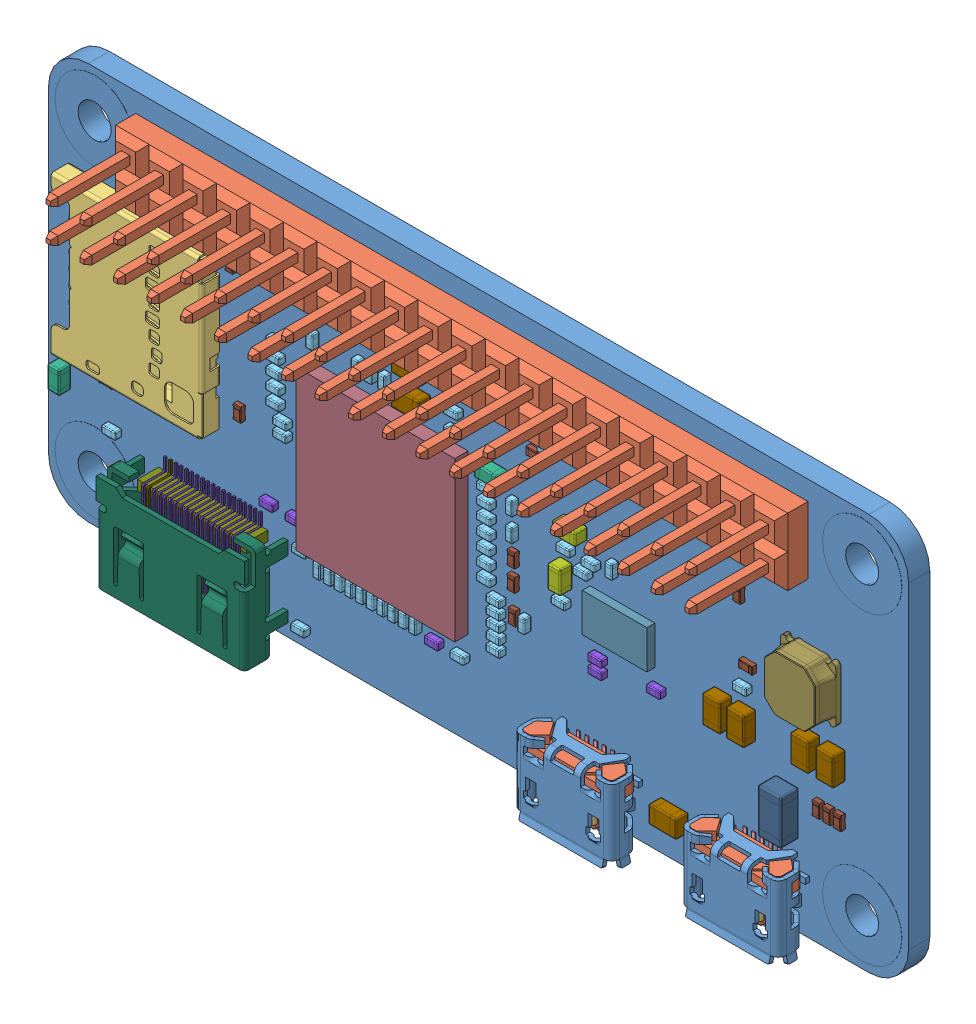
SolidWorks assembly Raspberry PI Zero W, configuration Default. Lengths in mm.
Overall size (65 30.65 11.38).
130 component instances, 22 part files, 0 mates.
Components (placement in the parent):
- Raspberry PI Zero W.step-1: Raspberry PI Zero W.step [Default] at origin size (65 32.42 20.3)
  - micro_usb_connector v17.step-1: micro_usb_connector v17.step [Default] at (41.4 3 1.74) x (0 -1 0) z (0 0 1) size (5.84 7.77 3.4)
    - shield.step-1: shield.step [Default] at origin size (5.84 7.77 3.4)
    - socket_housing.step-1: socket_housing.step [Default] at origin size (4.25 6.85 2.15)
    - socket_plate.step-1: socket_plate.step [Default] at origin size (3.38 6.8 0.31)
    - terminal.step-1: terminal.step [Default] at origin size (3.22 0.35 1.72)
    - terminal.step-2: terminal.step [Default] at (0 -1.3 0) size (3.22 0.35 1.72)
    - terminal.step-3: terminal.step [Default] at (0 -0.65 0) size (3.22 0.35 1.72)
    - terminal.step-4: terminal.step [Default] at (0 0.65 0) size (3.22 0.35 1.72)
    - terminal.step-5: terminal.step [Default] at (0 1.3 0) size (3.22 0.35 1.72)
  - micro_usb_connector v17.step-2: micro_usb_connector v17.step [Default] at (54 3 1.74) x (0 -1 0) z (0 0 1) size (5.84 7.77 3.4)
    - shield.step-1: shield.step [Default] at origin size (5.84 7.77 3.4)
    - socket_housing.step-1: socket_housing.step [Default] at origin size (4.25 6.85 2.15)
    - socket_plate.step-1: socket_plate.step [Default] at origin size (3.38 6.8 0.31)
    - terminal.step-1: terminal.step [Default] at origin size (3.22 0.35 1.72)
    - terminal.step-2: terminal.step [Default] at (0 -1.3 0) size (3.22 0.35 1.72)
    - terminal.step-3: terminal.step [Default] at (0 -0.65 0) size (3.22 0.35 1.72)
    - terminal.step-4: terminal.step [Default] at (0 0.65 0) size (3.22 0.35 1.72)
    - terminal.step-5: terminal.step [Default] at (0 1.3 0) size (3.22 0.35 1.72)
  - Components.step-1: Components.step [Default] at origin size (59.43 22.49 1.8)
    - CAPC-0402-T0.55-BN.step-1: CAPC-0402-T0.55-BN.step [Default] at (33.3698 17.6201 1.6) size (1.05 0.55 0.55)
    - CAPC-0402-T0.55-BN.step-2: CAPC-0402-T0.55-BN.step [Default] at (33.3698 16.6201 1.6) size (1.05 0.55 0.55)
    - CAPC-0402-T0.55-BN.step-3: CAPC-0402-T0.55-BN.step [Default] at (33.3698 15.6201 1.6) size (1.05 0.55 0.55)
    - CAPC-0402-T0.55-BN.step-4: CAPC-0402-T0.55-BN.step [Default] at (33.3698 14.6201 1.6) size (1.05 0.55 0.55)
    - CAPC-0402-T0.55-BN.step-5: CAPC-0402-T0.55-BN.step [Default] at (33.3698 13.6201 1.6) size (1.05 0.55 0.55)
    - CAPC-0402-T0.55-BN.step-6: CAPC-0402-T0.55-BN.step [Default] at (33.3698 12.6201 1.6) size (1.05 0.55 0.55)
    - CAPC-0402-T0.55-BN.step-7: CAPC-0402-T0.55-BN.step [Default] at (33.3698 11.6201 1.6) size (1.05 0.55 0.55)
    - CAPC-0402-T0.55-BN.step-8: CAPC-0402-T0.55-BN.step [Default] at (35.2975 17.3433 1.6) x (0 -1 0) z (0 0 1) size (1.05 0.55 0.55)
    - CAPC-0402-T0.55-BN.step-9: CAPC-0402-T0.55-BN.step [Default] at (35.2975 15.5933 1.6) x (0 -1 0) z (0 0 1) size (1.05 0.55 0.55)
    - CAPC-0402-T0.55-BN.step-10: CAPC-0402-T0.55-BN.step [Default] at (20.7555 5.9273 1.6) x (0 -1 0) z (0 0 1) size (1.05 0.55 0.55)
    - CAPC-0402-T0.55-BN.step-11: CAPC-0402-T0.55-BN.step [Default] at (21.5605 5.9273 1.6) x (0 -1 0) z (0 0 1) size (1.05 0.55 0.55)
    - CAPC-0402-T0.55-BN.step-12: CAPC-0402-T0.55-BN.step [Default] at (22.3655 5.9273 1.6) x (0 -1 0) z (0 0 1) size (1.05 0.55 0.55)
    - CAPC-0402-T0.55-BN.step-13: CAPC-0402-T0.55-BN.step [Default] at (23.1705 5.9273 1.6) x (0 -1 0) z (0 0 1) size (1.05 0.55 0.55)
    - CAPC-0402-T0.55-BN.step-14: CAPC-0402-T0.55-BN.step [Default] at (23.9755 5.9273 1.6) x (0 -1 0) z (0 0 1) size (1.05 0.55 0.55)
    - CAPC-0402-T0.55-BN.step-15: CAPC-0402-T0.55-BN.step [Default] at (24.7805 5.9273 1.6) x (0 -1 0) z (0 0 1) size (1.05 0.55 0.55)
    - CAPC-0402-T0.55-BN.step-16: CAPC-0402-T0.55-BN.step [Default] at (25.5855 5.9273 1.6) x (0 -1 0) z (0 0 1) size (1.05 0.55 0.55)
    - CAPC-0402-T0.55-BN.step-17: CAPC-0402-T0.55-BN.step [Default] at (26.3905 5.9273 1.6) x (0 -1 0) z (0 0 1) size (1.05 0.55 0.55)
    - CAPC-0402-T0.55-BN.step-18: CAPC-0402-T0.55-BN.step [Default] at (27.1955 5.9273 1.6) x (0 -1 0) z (0 0 1) size (1.05 0.55 0.55)
    - CAPC-0402-T0.55-BN.step-19: CAPC-0402-T0.55-BN.step [Default] at (28.0005 5.9273 1.6) x (0 -1 0) z (0 0 1) size (1.05 0.55 0.55)
    - CAPC-0402-T0.55-BN.step-20: CAPC-0402-T0.55-BN.step [Default] at (34.1 10.6 1.6) size (1.05 0.55 0.55)
    - CAPC-0402-T0.55-BN.step-21: CAPC-0402-T0.55-BN.step [Default] at (34.1 9.79 1.6) size (1.05 0.55 0.55)
    - CAPC-0402-T0.55-BN.step-22: CAPC-0402-T0.55-BN.step [Default] at (34.1 8.98 1.6) size (1.05 0.55 0.55)
    - CAPC-0402-T0.55-BN.step-23: CAPC-0402-T0.55-BN.step [Default] at (34.1 8.17 1.6) size (1.05 0.55 0.55)
    - CAPC-0402-T0.55-BN.step-24: CAPC-0402-T0.55-BN.step [Default] at (34.1 7.36 1.6) size (1.05 0.55 0.55)
    - CAPC-0402-T0.55-BN.step-25: CAPC-0402-T0.55-BN.step [Default] at (17.4437 19.1633 1.6) size (1.05 0.55 0.55)
    - CAPC-0402-T0.55-BN.step-26: CAPC-0402-T0.55-BN.step [Default] at (17.4437 18.1633 1.6) size (1.05 0.55 0.55)
    - CAPC-0402-T0.55-BN.step-27: CAPC-0402-T0.55-BN.step [Default] at (17.4437 17.1633 1.6) size (1.05 0.55 0.55)
    - CAPC-0402-T0.55-BN.step-28: CAPC-0402-T0.55-BN.step [Default] at (17.4437 16.1633 1.6) size (1.05 0.55 0.55)
    - CAPC-0402-T0.55-BN.step-29: CAPC-0402-T0.55-BN.step [Default] at (17.4437 15.1633 1.6) size (1.05 0.55 0.55)
    - CAPC-0402-T0.55-BN.step-30: CAPC-0402-T0.55-BN.step [Default] at (17.9697 14.164 1.6) size (1.05 0.55 0.55)
    - CAPC-0402-T0.55-BN.step-31: CAPC-0402-T0.55-BN.step [Default] at (17.9697 13.344 1.6) size (1.05 0.55 0.55)
    - CAPC-0402-T0.55-BN.step-32: CAPC-0402-T0.55-BN.step [Default] at (31.3668 5.5372 1.6) size (1.05 0.55 0.55)
    - CAPC-0402-T0.55-BN.step-33: CAPC-0402-T0.55-BN.step [Default] at (36.2259 10.107 1.6) x (0 -1 0) z (0 0 1) size (1.05 0.55 0.55)
    - CAPC-0402-T0.55-BN.step-34: CAPC-0402-T0.55-BN.step [Default] at (30.8759 20.015 1.6) size (1.05 0.55 0.55)
    - CAPC-0402-T0.55-BN.step-35: CAPC-0402-T0.55-BN.step [Default] at (25.6574 20.7007 1.6) x (0 -1 0) z (0 0 1) size (1.05 0.55 0.55)
    - CAPC-0402-T0.55-BN.step-36: CAPC-0402-T0.55-BN.step [Default] at (24.6574 20.7007 1.6) x (0 -1 0) z (0 0 1) size (1.05 0.55 0.55)
    - CAPC-0402-T0.55-BN.step-37: CAPC-0402-T0.55-BN.step [Default] at (23.6574 20.7007 1.6) x (0 -1 0) z (0 0 1) size (1.05 0.55 0.55)
    - CAPC-0402-T0.55-BN.step-38: CAPC-0402-T0.55-BN.step [Default] at (20.2103 20.6923 1.6) x (0 -1 0) z (0 0 1) size (1.05 0.55 0.55)
    - CAPC-0402-T0.55-BN.step-39: CAPC-0402-T0.55-BN.step [Default] at (39.0204 12.9386 1.6) size (1.05 0.55 0.55)
    - CAPC-0402-T0.55-BN.step-40: CAPC-0402-T0.55-BN.step [Default] at (40.6631 15.6901 1.6) size (1.05 0.55 0.55)
    - CAPC-0402-T0.55-BN.step-41: CAPC-0402-T0.55-BN.step [Default] at (39.3678 16.5618 1.6) size (1.05 0.55 0.55)
    - CAPC-0402-T0.55-BN.step-42: CAPC-0402-T0.55-BN.step [Default] at (42.831 16.9675 1.6) x (0 -1 0) z (0 0 1) size (1.05 0.55 0.55)
    - CAPC-0402-T0.55-BN.step-43: CAPC-0402-T0.55-BN.step [Default] at (41.2678 16.5618 1.6) size (1.05 0.55 0.55)
    - CAPC-0402-T0.55-BN.step-44: CAPC-0402-T0.55-BN.step [Default] at (5.0529 7.1196 1.6) size (1.05 0.55 0.55)
    - CAPC-0402-T0.55-BN.step-45: CAPC-0402-T0.55-BN.step [Default] at (37.9324 22.363 1.6) size (1.05 0.55 0.55)
    - CAPC-0402-T0.55-BN.step-46: CAPC-0402-T0.55-BN.step [Default] at (52.706 14.1667 1.6) size (1.05 0.55 0.55)
    - CAPC-0603-T0.9-BN.step-1: CAPC-0603-T0.9-BN.step [Default] at (1.2622 8.8622 1.6) x (0 -1 0) z (0 0 1) size (1.7 0.9 0.9)
    - CAPC-0402-T0.55-BN.step-47: CAPC-0402-T0.55-BN.step [Default] at (19.3797 6.5002 1.6) size (1.05 0.55 0.55)
    - CAPC-0402-T0.55-BN.step-48: CAPC-0402-T0.55-BN.step [Default] at (19.3316 1.3043 1.6) size (1.05 0.55 0.55)
    - CAPC-0603-T0.9-BN.step-2: CAPC-0603-T0.9-BN.step [Default] at (33.8953 18.8389 1.6) size (1.7 0.9 0.9)
    - INDC-0603.step-1: INDC-0603.step [Default] at (39.8621 18.1224 1.6) size (1.75 0.95 0.95)
    - INDC-0603.step-2: INDC-0603.step [Default] at (39.1295 14.7453 1.6) x (0 -1 0) z (0 0 1) size (1.75 0.95 0.95)
    - INDC-0402.step-1: INDC-0402.step [Default] at (29.426 5.5149 1.6) size (1.05 0.55 0.55)
    - INDC-0402.step-2: INDC-0402.step [Default] at (41.7855 10.5602 1.6) size (1.05 0.55 0.55)
    - INDC-0402.step-3: INDC-0402.step [Default] at (41.7855 9.7502 1.6) size (1.05 0.55 0.55)
    - INDC-0402.step-4: INDC-0402.step [Default] at (46.2071 10.726 1.6) size (1.05 0.55 0.55)
    - INDC-0402.step-5: INDC-0402.step [Default] at (18.9188 8.3162 1.6) size (1.05 0.55 0.55)
    - INDC-0402.step-6: INDC-0402.step [Default] at (16.9188 8.3162 1.6) size (1.05 0.55 0.55)
    - CAPC-0805-T0.95-BN.step-1: CAPC-0805-T0.95-BN.step [Default] at (27.8612 20.5927 1.6) size (2.1 1.35 0.95)
    - CAPC-0805-T0.95-BN.step-2: CAPC-0805-T0.95-BN.step [Default] at (27.8612 22.8427 1.6) size (2.1 1.35 0.95)
    - CAPC-0805-T0.95-BN.step-3: CAPC-0805-T0.95-BN.step [Default] at (51.017 11.9186 1.6) x (0 -1 0) z (0 0 1) size (2.1 1.35 0.95)
    - CAPC-0805-T0.95-BN.step-4: CAPC-0805-T0.95-BN.step [Default] at (52.817 11.9186 1.6) x (0 -1 0) z (0 0 1) size (2.1 1.35 0.95)
    - CAPC-0805-T0.95-BN.step-5: CAPC-0805-T0.95-BN.step [Default] at (57.6691 12.6645 1.6) x (0 -1 0) z (0 0 1) size (2.1 1.35 0.95)
    - CAPC-0805-T0.95-BN.step-6: CAPC-0805-T0.95-BN.step [Default] at (59.5691 12.6645 1.6) x (0 -1 0) z (0 0 1) size (2.1 1.35 0.95)
    - CAPC-1206-T1.4-BN.step-1: CAPC-1206-T1.4-BN.step [Default] at (55.8544 7.8017 1.6) x (0 -1 0) z (0 0 1) size (3.35 1.75 1.4)
    - CAPC-0805-T0.95-BN.step-7: CAPC-0805-T0.95-BN.step [Default] at (47.3323 2.998 1.6) size (2.1 1.35 0.95)
    - RESC-0402.step-1: RESC-0402.step [Default] at (35.3052 13.8988 1.6) x (0 -1 0) z (0 0 1) size (1.05 0.55 0.4)
    - RESC-0402.step-2: RESC-0402.step [Default] at (35.3052 12.2988 1.6) x (0 -1 0) z (0 0 1) size (1.05 0.55 0.4)
    - RESC-0402.step-3: RESC-0402.step [Default] at (35.3713 10.1216 1.6) x (0 -1 0) z (0 0 1) size (1.05 0.55 0.4)
    - RESC-0402.step-4: RESC-0402.step [Default] at (14.6084 13.087 1.6) x (0 1 0) z (0 0 1) size (1.05 0.55 0.4)
    - RESC-0402.step-5: RESC-0402.step [Default] at (13.9844 22.5264 1.6) x (0 -1 0) z (0 0 1) size (1.05 0.55 0.4)
    - RESC-0402.step-6: RESC-0402.step [Default] at (15.3844 22.5264 1.6) x (0 -1 0) z (0 0 1) size (1.05 0.55 0.4)
    - RESC-0402.step-7: RESC-0402.step [Default] at (4.6621 10.2008 1.6) size (1.05 0.55 0.4)
    - RESC-0402.step-8: RESC-0402.step [Default] at (58.3516 9.0224 1.6) x (0 1 0) z (0 0 1) size (1.05 0.55 0.4)
    - RESC-0402.step-9: RESC-0402.step [Default] at (59.1516 9.0224 1.6) x (0 1 0) z (0 0 1) size (1.05 0.55 0.4)
    - RESC-0402.step-10: RESC-0402.step [Default] at (59.9516 9.0224 1.6) x (0 1 0) z (0 0 1) size (1.05 0.55 0.4)
    - RESC-0402.step-11: RESC-0402.step [Default] at (36.9521 21.579 1.6) size (1.05 0.55 0.4)
    - CAPC-0402-T0.55-BN.step-49: CAPC-0402-T0.55-BN.step [Default] at (30.8759 21.315 1.6) size (1.05 0.55 0.55)
    - RESC-0402.step-12: RESC-0402.step [Default] at (47.4882 18.8168 1.6) x (0.707107 0.707107 0) z (0 0 1) size (1.05 0.55 0.4)
    - RESC-0402.step-13: RESC-0402.step [Default] at (52.3627 20.1006 1.6) x (0 1 0) z (0 0 1) size (1.05 0.55 0.4)
    - RESC-0402.step-14: RESC-0402.step [Default] at (53.0236 15.6867 1.6) size (1.05 0.55 0.4)
    - SRN4018.step-1: SRN4018.step [Default] at (57.7919 17.1897 1.6) size (4.2 4.2 1.8)
    - Components-0.step-1: Components-0.step [Default] at origin size (12.01 12.01 1)
    - Components-1.step-1: Components-1.step [Default] at origin size (4.88 2.9 0.6)
  - Mini HDMI.step-1: Mini HDMI.step [Default] at (12.5 5.85 3.1) x (0 -1 0) z (0 0 1) size (16.55 11.21 19.45)
    - Housing.step-1: Housing.step [Default] at origin size (16.55 9.35 15.8) (hidden)
    - Shielding.step-1: Shielding.step [Default] at (2.875 0 0.82) x (0 1 0) z (0 0 1) size (11.21 7.6 5.45)
    - Housing2.step-1: Housing2.step [Default] at (-0.075 0 -0.65) x (0 -1 0) z (0 0 1) size (8.25 0.75 1.6)
    - Pin1.step-1: Pin1.step [Default] at (2.1 -3.6 0.3) size (5.9 0.15 1.8)
    - Pin1.step-2: Pin1.step [Default] at (2.1 -2.8 0.3) size (5.9 0.15 1.8)
    - Pin1.step-3: Pin1.step [Default] at (2.1 -2.4 0.3) size (5.9 0.15 1.8)
    - Pin1.step-4: Pin1.step [Default] at (2.1 -2 0.3) size (5.9 0.15 1.8)
    - Pin1.step-5: Pin1.step [Default] at (2.1 -1.6 0.3) size (5.9 0.15 1.8)
    - Pin1.step-6: Pin1.step [Default] at (2.1 -1.2 0.3) size (5.9 0.15 1.8)
    - Pin1.step-7: Pin1.step [Default] at (2.1 -0.8 0.3) size (5.9 0.15 1.8)
    - Pin1.step-8: Pin1.step [Default] at (2.1 -0.4 0.3) size (5.9 0.15 1.8)
    - Pin1.step-9: Pin1.step [Default] at (2.1 0 0.3) size (5.9 0.15 1.8)
    - Pin1.step-10: Pin1.step [Default] at (2.1 0.4 0.3) size (5.9 0.15 1.8)
    - Pin1.step-11: Pin1.step [Default] at (2.1 0.8 0.3) size (5.9 0.15 1.8)
    - Pin1.step-12: Pin1.step [Default] at (2.1 1.2 0.3) size (5.9 0.15 1.8)
    - Pin1.step-13: Pin1.step [Default] at (2.1 1.6 0.3) size (5.9 0.15 1.8)
    - Pin1.step-14: Pin1.step [Default] at (2.1 2 0.3) size (5.9 0.15 1.8)
    - Pin1.step-15: Pin1.step [Default] at (2.1 2.4 0.3) size (5.9 0.15 1.8)
    - Pin1.step-16: Pin1.step [Default] at (2.1 2.8 0.3) size (5.9 0.15 1.8)
    - Pin1.step-17: Pin1.step [Default] at (2.1 3.2 0.3) size (5.9 0.15 1.8)
    - Pin1.step-18: Pin1.step [Default] at (2.1 3.6 0.3) size (5.9 0.15 1.8)
    - Pin2.step-1: Pin2.step [Default] at (1.7983 -3.2 0.3) size (5.3 0.15 1.8)
  - Board.step-1: Board.step [Default] at origin size (65 30 1.62)
  - HDRV40W64P254_2X20_5080X508X838B.step-1: HDRV40W64P254_2X20_5080X508X838B.step [Default] at (8.37 27.77 1.6) size (50.8 5.08 11.38)
  - Micro SD slot.step-1: Micro SD slot.step [Default] at (7.3191 16.9624 1.57) x (0 -1 0) z (-1 0 0) size (11.95 1.45 11.4)
